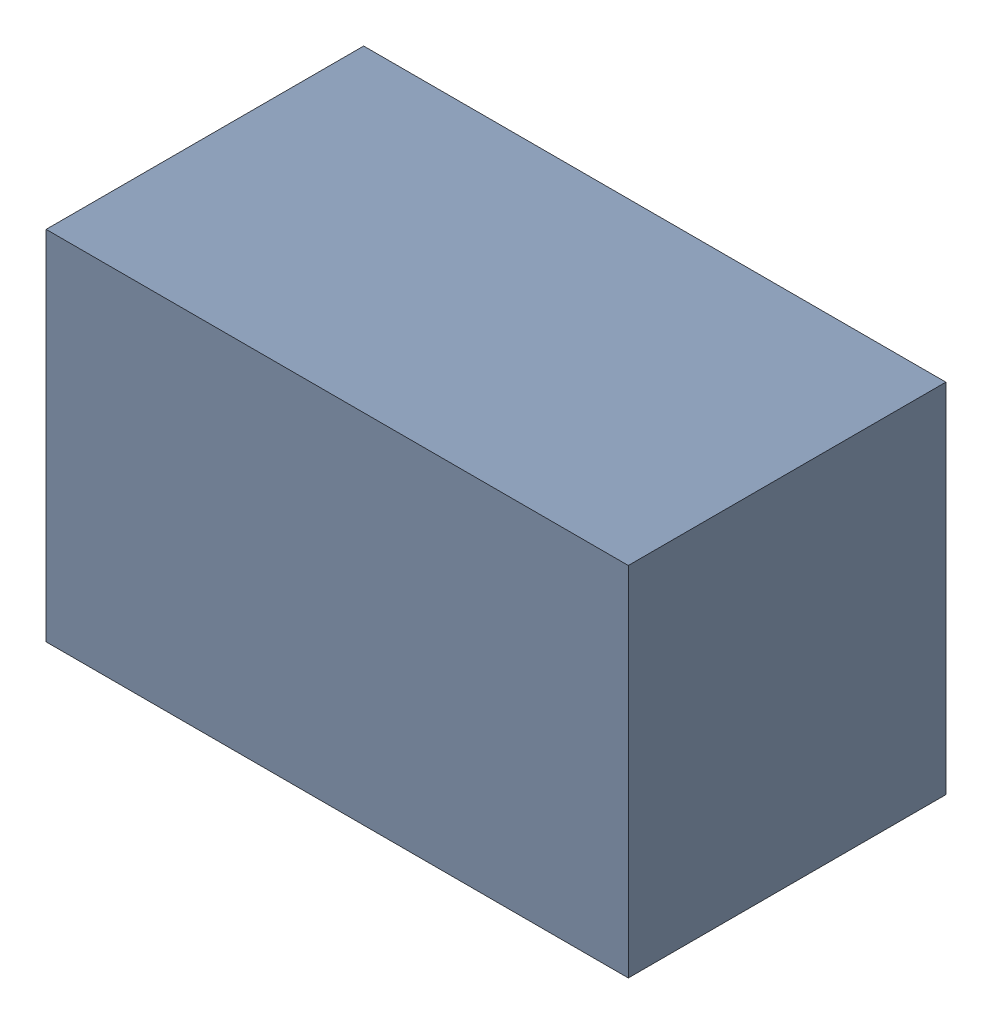
SolidWorks assembly CP1_1, configuration Default. Lengths in mm.
Overall size (2.2 1.35 1.2).
2 component instances, 1 part files, 0 mates.
Components (placement in the parent):
- 407988128-1: 407988128 [Default] at (65.024 6.604 0.0127) size (2.2 1.35 1.2)
  - Extruded_9-1: Extruded_9 [Default] at origin size (2.2 1.35 1.2)
